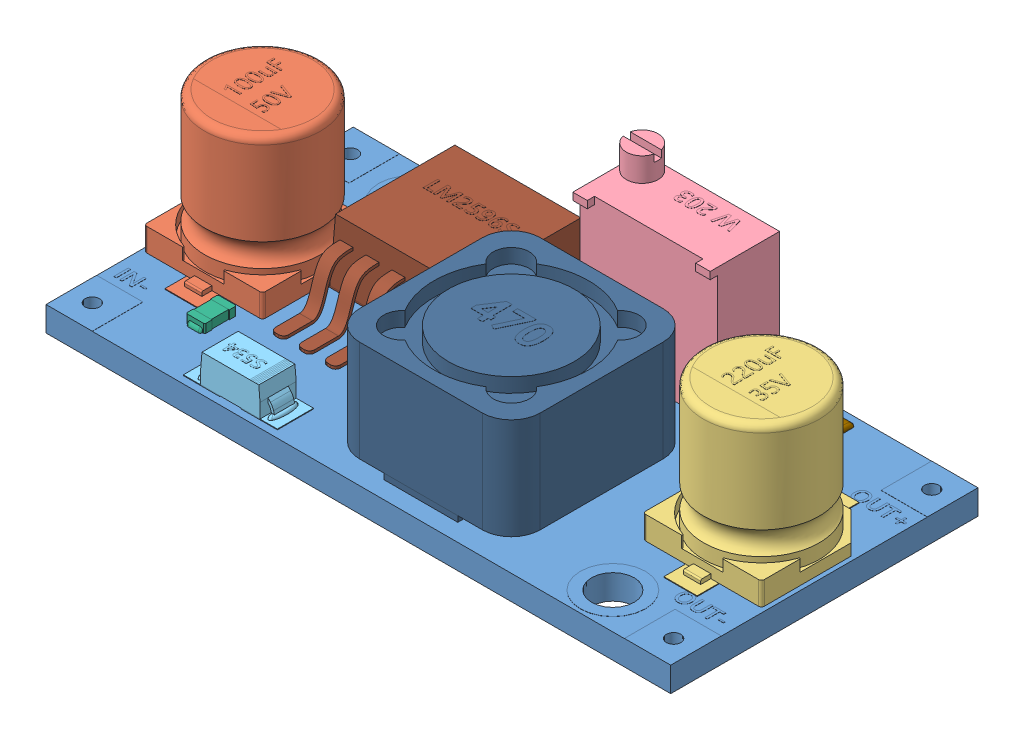
SolidWorks assembly converterLM2596, configuration Default. Lengths in mm.
Overall size (43.2 15.15 21.25).
12 component instances, 11 part files, 23 mates.
Components (placement in the parent):
- lm2596board-1: lm2596board [Default] at origin size (43.2 1.71 21.25)
- smd100uF-1: smd100uF [Default] at (-17.25 2.55 0) x (0 0 -1) z (1 0 0) size (11.2 9.76 8.2)
- smd220uF-2: smd220uF [Default] at (17.25 2.55 0) x (0 0 -1) z (1 0 0) size (11.2 9.76 8.2)
- TrimmerW203-1: TrimmerW203 [Default] at (4.6271 6.95 -9.1276) size (9.5 15.15 4.81)
- smdS537diode-1: smdS537diode [Default] at (-9.35 1.75 8.875) x (-1 0 0) z (0 0 -1) size (6.5 2.13 2.5)
- smdceramiccapacitor-1: smdceramiccapacitor [Default] at (-15 1.7 5.7969) x (0 0 1) z (-1 0 0) size (2.55 0.62 1.3)
- smdceramiccapacitor-2: smdceramiccapacitor [Default] at (-1.3196 1.7 -5.2916) x (0 0 1) z (-1 0 0) size (2.55 0.62 1.3)
- smdResistor331-1: smdResistor331 [Default] at (-1.2696 1.7 -8.4665) x (0 0 1) z (-1 0 0) size (2.54 0.62 1.34)
- smdResistor102-1: smdResistor102 [Default] at (10.7771 1.7 -8.4665) x (0 0 -1) z (1 0 0) size (2.54 0.62 1.34)
- smdLED-1: smdLED [Default] at (13.0521 1.75 -8.4701) x (0 0 -1) z (1 0 0) size (3.2 0.84 1.28)
- smbInductor470-1: smbInductor470 [Default] at (3.1271 2.1 3.175) size (12.5 7.41 12.5)
- LM2596S-1: LM2596S [Default] at (-8.0627 1.8 -4.5407) size (9.8 4.61 14.95)
Mates (geometry in assembly coordinates):
- Coincident2: coincident: plane of lm2596board-1 through (0 1.7 0) normal (0 1 0); plane of smd100uF-1 through (-17.25 1.7 0) normal (0 -1 0)
- Coincident3: coincident: plane of smd100uF-1 through (-17.25 2.55 0) normal (0 0 -1); plane of assembly through (0 0 0) normal (0 0 1)
- Distance1: distance = 0.25 mm: plane of smd100uF-1 through (-21.35 1.75 -4.1) normal (-1 0 0); plane of lm2596board-1 through (-21.6 1.7 10.625) normal (-1 0 0)
- Coincident5: coincident: plane of smd100uF-1 through (-21.35 1.75 4.1) normal (0 0 1); plane of smd220uF-2 through (13.15 1.75 4.1) normal (0 0 1)
- Coincident6: coincident: plane of lm2596board-1 through (0 1.7 0) normal (0 1 0); plane of smd220uF-2 through (17.25 1.7 0) normal (0 -1 0)
- Distance2: distance = 0.25 mm: plane of smd220uF-2 through (21.35 1.75 -4.1) normal (1 0 0); plane of lm2596board-1 through (21.6 1.7 10.625) normal (1 0 0)
- Coincident8: coincident: plane of lm2596board-1 through (0 1.7 0) normal (0 1 0); plane of TrimmerW203-1 through (-0.1229 1.7 -4.8276) normal (0 -1 0)
- Coincident9: coincident: plane of lm2596board-1 through (0 1.7 0) normal (0 1 0); plane of smdS537diode-1 through (-9.35 1.7 8.875) normal (0 -1 0)
- Distance3: distance = 0.5 mm: plane of smdS537diode-1 through (-7.3 3.75 10.125) normal (0 0 1); plane of lm2596board-1 through (-21.6 1.7 10.625) normal (0 0 1)
- Distance4: distance = 10.2 mm: plane of smdS537diode-1 through (-11.4 3.75 7.625) normal (-1 0 0); plane of lm2596board-1 through (-21.6 1.7 10.625) normal (-1 0 0)
- Coincident12: coincident: plane of lm2596board-1 through (0 1.7 0) normal (0 1 0); plane of smdceramiccapacitor-1 through (-15 1.7 5.7969) normal (0 -1 0)
- Distance5: distance = 6 mm: plane of smdceramiccapacitor-1 through (-15.6 3.9971 5.1969) normal (-1 0 0); plane of lm2596board-1 through (-21.6 1.7 10.625) normal (-1 0 0)
- Coincident14: coincident: plane of lm2596board-1 through (0 1.7 0) normal (0 1 0); plane of smdResistor331-1 through (-1.2696 1.7 -8.4665) normal (0 -1 0)
- Coincident16: coincident: plane of smdceramiccapacitor-2 through (-1.9196 3.9971 -5.8916) normal (-1 0 0); plane of smdResistor331-1 through (-1.9196 2.3 -9.5665) normal (-1 0 0)
- Coincident17: coincident: plane of lm2596board-1 through (0 1.7 0) normal (0 1 0); plane of smdResistor102-1 through (10.7771 1.7 -8.4665) normal (0 -1 0)
- Distance6: distance = 0.75 mm: plane of smdResistor102-1 through (10.1271 2.3 -7.3665) normal (-1 0 0); plane of TrimmerW203-1 through (9.3771 2.2 -4.8276) normal (1 0 0)
- Coincident19: coincident: plane of smdResistor331-1 through (-1.9196 2.3 -9.5665) normal (0 0 -1); plane of smdResistor102-1 through (11.4271 2.3 -9.5665) normal (0 0 -1)
- Coincident20: coincident: plane of lm2596board-1 through (0 1.7 0) normal (0 1 0); plane of smdLED-1 through (13.0521 1.7 -8.4701) normal (0 -1 0)
- Distance7: distance = 1 mm: plane of smdLED-1 through (12.4271 2.5 -7.8451) normal (-1 0 0); plane of smdResistor102-1 through (11.4271 2.3 -7.3665) normal (1 0 0)
- Coincident22: coincident: plane of lm2596board-1 through (0 1.7 0) normal (0 1 0); plane of smbInductor470-1 through (3.1271 1.7 3.175) normal (0 -1 0)
- Coincident24: coincident: plane of TrimmerW203-1 through (9.3771 2.2 -4.8276) normal (1 0 0); plane of smbInductor470-1 through (9.3771 9.1 9.425) normal (1 0 0)
- Distance8: distance = 1.2 mm: plane of smbInductor470-1 through (-3.1229 9.1 9.425) normal (0 0 1); plane of lm2596board-1 through (-21.6 1.7 10.625) normal (0 0 1)
- Coincident26: coincident: plane of lm2596board-1 through (0 1.7 0) normal (0 1 0); plane of LM2596S-1 through (-8.0627 1.7 -4.5407) normal (0 -1 0)
